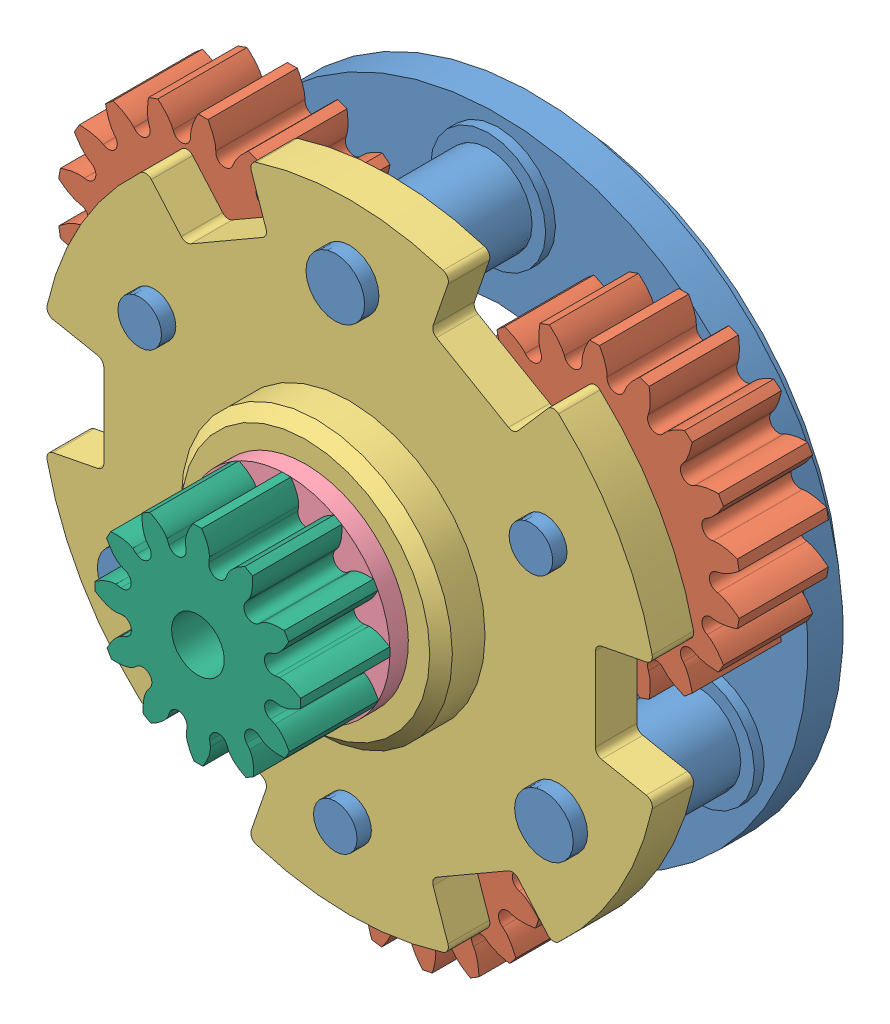
SolidWorks assembly OrangeSet, configuration Default. Lengths in mm.
Overall size (28.32 28.58 12.03).
9 component instances, 6 part files, 12 mates.
Components (placement in the parent):
- OrangeArmDisk-1: OrangeArmDisk [Default] at (4.7459 12.4443 16.6159) size (20.9 20.9 7.39)
- OrangePlanetGear-1: OrangePlanetGear [Default] at (-1.8532 16.2543 18.1399) x (0.94019 -0.340651 0) z (0 0 1) size (9.76 9.86 3.01)
- OrangePlanetGear-2: OrangePlanetGear [Default] at (4.7459 4.8243 18.1399) x (0.625912 0.779893 0) z (0 0 1) size (9.76 9.86 3.01)
- OrangePlanetGear-3: OrangePlanetGear [Default] at (11.345 16.2543 18.1399) size (9.76 9.86 3.01)
- OrangeDriveDisk-1: OrangeDriveDisk [Default] at (4.7459 12.4443 22.8135) x (0.5 -0.866025 0) z (0 0 -1) size (20.43 20.9 2.98)
- OrangeSunGear-1: OrangeSunGear [Default] at (1.2412 9.6627 18.8537) x (0.868984 -0.49484 0) z (0 0 1) size (6.93 6.93 6.64)
  - OrangeIntermediaryPlate-1: OrangeIntermediaryPlate [Default] at (1.6691 4.1514 5.4457) size (6.93 6.93 0.62)
  - OrangeSpurSmall-2: OrangeSpurSmall [Default] at (1.6691 4.1514 2.4358) size (5.78 5.84 3.01)
  - OrangeSpurLarge-2: OrangeSpurLarge [Default] at (1.6691 4.1514 6.068) size (6.93 6.93 3.01)
Mates (geometry in assembly coordinates):
- Concentric1: concentric aligned: cylinder of OrangeArmDisk-1 through (-1.8532 16.2543 21.3149) axis (0 0 -1) radius 0.9779; cylinder of OrangePlanetGear-1 through (-1.8532 16.2543 21.1498) axis (0 0 -1) radius 1.016
- Coincident1: coincident anti-aligned: plane of OrangeArmDisk-1 through (-1.8532 16.2543 18.1399) normal (0 0 1); plane of OrangePlanetGear-1 through (-1.8532 16.2543 18.1399) normal (0 0 -1)
- Concentric2: concentric aligned: cylinder of OrangeArmDisk-1 through (4.7459 4.8243 21.3149) axis (0 0 -1) radius 0.9779; cylinder of OrangePlanetGear-2 through (4.7459 4.8243 21.1498) axis (0 0 -1) radius 1.016
- Coincident2: coincident anti-aligned: plane of OrangeArmDisk-1 through (4.7459 4.8243 18.1399) normal (0 0 1); plane of OrangePlanetGear-2 through (4.7459 4.8243 18.1399) normal (0 0 -1)
- Coincident3: coincident anti-aligned: plane of OrangeArmDisk-1 through (11.345 16.2543 18.1399) normal (0 0 1); plane of OrangePlanetGear-3 through (11.345 16.2543 18.1399) normal (0 0 -1)
- Concentric3: concentric aligned: cylinder of OrangeArmDisk-1 through (11.345 16.2543 21.3149) axis (0 0 -1) radius 0.9779; cylinder of OrangePlanetGear-3 through (11.345 16.2543 21.1498) axis (0 0 -1) radius 1.016
- Concentric4: concentric aligned: cylinder of OrangeArmDisk-1 through (4.7459 20.5723 23.2961) axis (0 0 -1) radius 0.9906; cylinder of OrangeDriveDisk-1 through (4.7459 20.5723 22.8135) axis (0 0 -1) radius 0.9906
- Coincident4: coincident anti-aligned: plane of OrangeArmDisk-1 through (4.7459 20.5723 21.3149) normal (0 0 1); plane of OrangeDriveDisk-1 through (-2.2931 8.3803 21.3149) normal (0 0 -1)
- Concentric5: concentric aligned: cylinder of OrangeArmDisk-1 through (11.345 16.2543 23.2961) axis (0 0 -1) radius 0.7366; cylinder of OrangeDriveDisk-1 through (11.345 16.2543 22.8135) axis (0 0 -1) radius 0.7366
- Concentric6: concentric aligned: cylinder of OrangeArmDisk-1 through (4.7459 12.4443 17.8097) axis (0 0 -1) radius 4.9276; cylinder of OrangeSunGear-1/OrangeSpurSmall-2 through (4.7459 12.4443 24.2994) axis (0 0 -1) radius 0.889
- Coincident5: coincident anti-aligned: plane of OrangeDriveDisk-1 through (4.7459 12.4443 24.2994) normal (0 0 1); plane of OrangeSunGear-1/OrangeIntermediaryPlate-1 through (4.7459 12.4443 24.2994) normal (0 0 -1)
- GearMate1: gear = 5.842 : 5.9944 mm: circle of OrangeDriveDisk-1; circle of OrangeSunGear-1/OrangeSpurSmall-2
